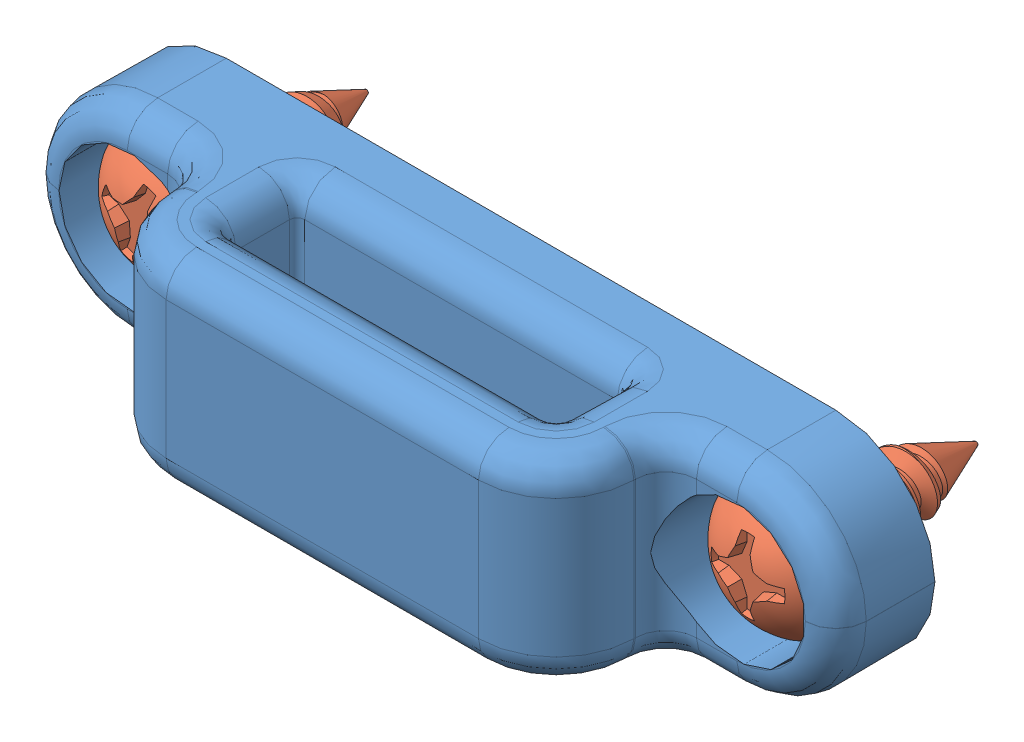
SolidWorks assembly footman_loop_with_screws, configuration Default. Lengths in mm.
Overall size (53 13.01 22.9).
3 component instances, 2 part files, 7 mates.
Components (placement in the parent):
- footman_loop-1: footman_loop [Default] at origin size (53 13.01 13.7)
- screw-1: screw [90190A194] at (-20 0 3.5) x (-0.310722 -0.950501 0) z (0 0 1) size (8.18 8.18 15.47)
- screw-2: screw [90190A194] at (20 0 3.5) size (8.18 8.18 15.47)
Mates (geometry in assembly coordinates):
- Coincident1: coordinate: point of footman_loop-1; point of assembly
- Coincident2: coincident: point of footman_loop-1; line of screw-1 through (-20 0 -12.648) axis (0 0 1)
- Coincident3: coincident: point of footman_loop-1; line of screw-2 through (20 0 2.8723) axis (0 0 1)
- Parallel1: parallel aligned: line of assembly; line of screw-1 through (-20 0 -12.648) axis (0 0 1)
- Parallel2: parallel aligned: line of ? through (20 0 2.8723) axis (0 0 1)
- Coincident4: coincident: plane of footman_loop-1 through (0 0 3.5) normal (0 0 1); point of screw-1
- Coincident5: coincident: plane of footman_loop-1 through (0 0 3.5) normal (0 0 1); point of screw-2
